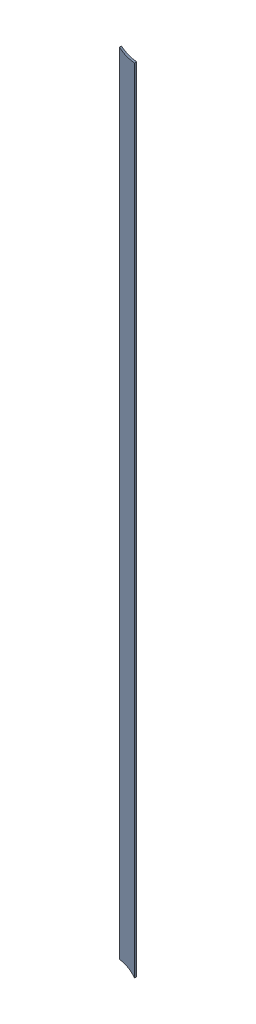
SolidWorks assembly Track (20.46mm,29.56mm)(20.46mm,43.24mm) on Bottom Layer, configuration Predeterminado. Lengths in mm.
Overall size (0.25 13.44 0.04).
2 component instances, 1 part files, 0 mates.
Components (placement in the parent):
- Track (20.46mm,29.56mm)(20.46mm,43.24mm) on Bottom Layer-1-1: Track (20.46mm,29.56mm)(20.46mm,43.24mm) on Bottom Layer-1 [Predeterminado] at (-68.317 -44.187 -0.4013) size (0.25 13.44 0.04)
  - Track (20.46mm,29.56mm)(20.46mm,43.24mm) on Bottom Layer-Part-1-1: Track (20.46mm,29.56mm)(20.46mm,43.24mm) on Bottom Layer-Part-1 [Predeterminado] at origin size (0.25 13.44 0.04)
